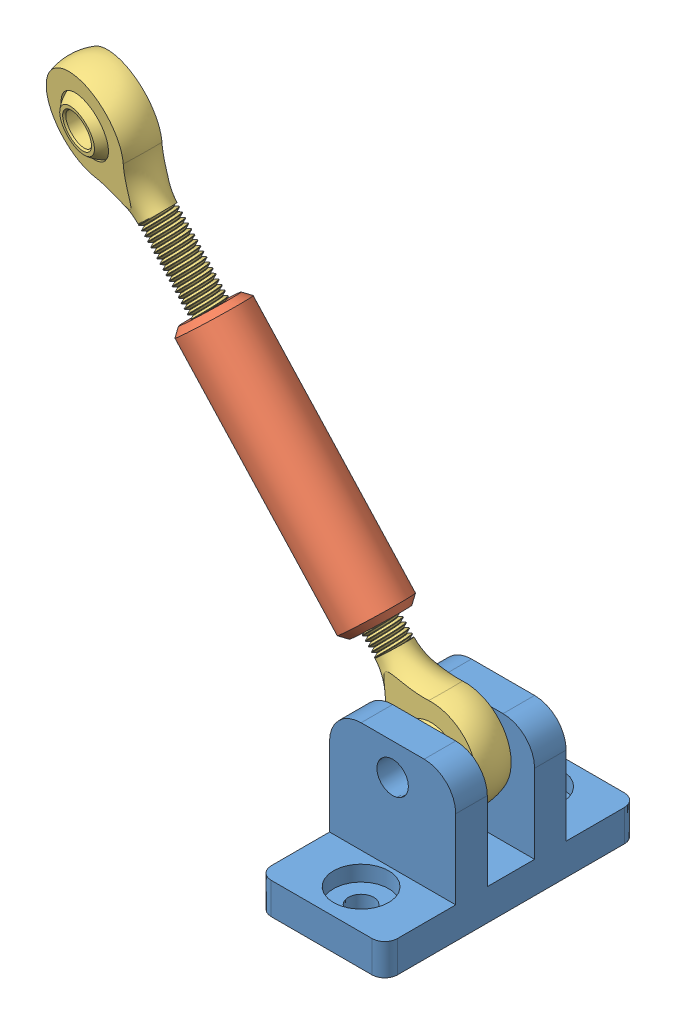
SolidWorks assembly 000061-R01_THRUST_MOUNT_ASSM, configuration Default. Lengths in mm.
Overall size (97.89 121.62 50.8).
4 component instances, 3 part files, 6 mates.
Components (placement in the parent):
- 000029-R01_LAUNCH_MOUNT_CLEVIS-1: 000029-R01_LAUNCH_MOUNT_CLEVIS [Default] at (42.386 21.9106 37.6303) size (31.75 38.1 50.8)
- THREADED_ROD-1: THREADED_ROD [Default] at (28.8494 58.8619 37.6303) x (0.147018 0.135141 0.979859) z (-0.721391 -0.663113 0.199693) size (12.7 50.8 12.7)
- 8405K111_THRUST-RATED BALL JOINT ROD END-1: 8405K111_THRUST-RATED BALL JOINT ROD END [8405K111] at (-16.0576 107.7155 37.6303) x (0.715999 0.658157 0.232754) z (-0.171358 -0.157515 0.972536) size (19.88 46.6 9.53)
- 8405K111_THRUST-RATED BALL JOINT ROD END-2: 8405K111_THRUST-RATED BALL JOINT ROD END [8405K111] at (31.6427 55.8231 37.6303) x (-0.736219 -0.676743 0) z (0 0 1) size (19.88 46.6 9.53)
Mates (geometry in assembly coordinates):
- Concentric1: concentric anti-aligned: cylinder of THREADED_ROD-1 through (28.8494 58.8619 37.6303) axis (0.676743 -0.736219 0) radius 2.5527; circle of 8405K111_THRUST-RATED BALL JOINT ROD END-2
- Concentric2: concentric anti-aligned: cylinder of THREADED_ROD-1 through (-5.5292 96.2618 37.6303) axis (-0.676743 0.736219 0) radius 2.5527; circle of 8405K111_THRUST-RATED BALL JOINT ROD END-1
- LimitDistance1: limit distance = 5.08 mm anti-aligned: plane of 8405K111_THRUST-RATED BALL JOINT ROD END-1 through (-2.0913 92.5218 37.6303) normal (0.676743 -0.736219 0); plane of THREADED_ROD-1 through (-5.5292 96.2618 37.6303) normal (-0.676743 0.736219 0)
- LimitDistance2: limit distance = 16.51 mm anti-aligned: plane of 8405K111_THRUST-RATED BALL JOINT ROD END-2 through (17.6764 71.0168 37.6303) normal (-0.676743 0.736219 0); plane of THREADED_ROD-1 through (28.8494 58.8619 37.6303) normal (0.676743 -0.736219 0)
- Concentric3: concentric anti-aligned: cylinder of 000029-R01_LAUNCH_MOUNT_CLEVIS-1 through (42.386 44.1356 63.0303) axis (0 0 -1) radius 3.175; cylinder of 8405K111_THRUST-RATED BALL JOINT ROD END-2 through (42.386 44.1356 32.8678) axis (0 0 1) radius 3.175
- Coincident4: coincident anti-aligned: plane of 000029-R01_LAUNCH_MOUNT_CLEVIS-1 through (42.386 21.9106 37.6303) normal (0 0 -1); plane of 8405K111_THRUST-RATED BALL JOINT ROD END-2 through (31.6427 55.8231 37.6303) normal (0 0 1)
